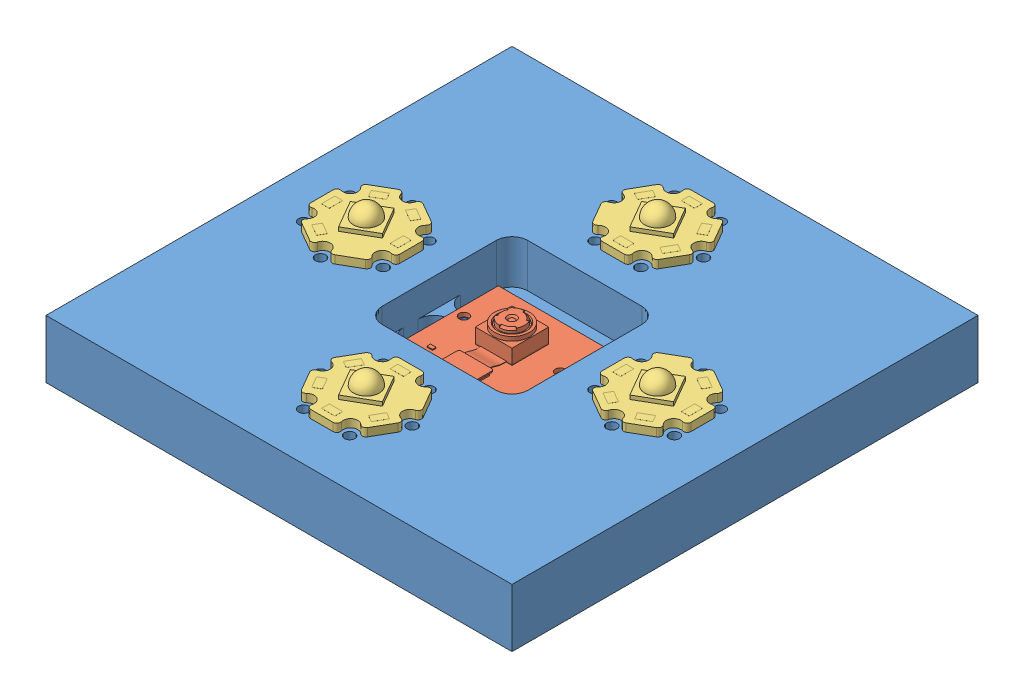
SolidWorks assembly Flashlight, configuration Default. Lengths in mm.
Overall size (101.6 18.1 101.6).
6 component instances, 3 part files, 5 mates.
Components (placement in the parent):
- LED Plate-1: LED Plate [Default] at (26.4563 39.58 55.3504) size (101.6 12.7 101.6)
- RasPi_Camera-1: RasPi_Camera [Default] at (26.4247 47.3817 55.2918) size (25 8.25 24)
- LZ4-40G108-0000-1: LZ4-40G108-0000 [Default] at (26.4563 52.28 23.6004) x (0.500598 0 0.86568) z (-0.86568 0 0.500598) size (19.46 5.4 19.4)
- LZ4-40G108-0000-2: LZ4-40G108-0000 [Default] at (-5.2937 52.28 55.3504) x (0.86568 0 -0.500598) z (0.500598 0 0.86568) size (19.46 5.4 19.4)
- LZ4-40G108-0000-3: LZ4-40G108-0000 [Default] at (26.4563 52.28 87.1004) x (-0.500598 0 -0.86568) z (0.86568 0 -0.500598) size (19.46 5.4 19.4)
- LZ4-40G108-0000-4: LZ4-40G108-0000 [Default] at (58.2063 52.28 55.3504) x (-0.86568 0 0.500598) z (-0.500598 0 -0.86568) size (19.46 5.4 19.4)
Mates (geometry in assembly coordinates):
- Coincident1: coincident anti-aligned: plane of LED Plate-1 through (26.4563 52.28 55.3504) normal (0 1 0); plane of LZ4-40G108-0000-1 through (26.4563 52.28 23.6004) normal (0 -1 0)
- Concentric1: concentric anti-aligned: circle of LZ4-40G108-0000-1; line of LED Plate-1 through (26.4563 52.28 23.6004) axis (0 1 0)
- Concentric3: concentric aligned: line of LED Plate-1 through (26.4563 39.58 55.3504) axis (0 1 0); circle of RasPi_Camera-1
- Parallel3: parallel aligned: plane of LED Plate-1 through (77.2563 52.28 4.5504) normal (1 0 0); plane of RasPi_Camera-1 through (38.9247 45.93 69.7918) normal (1 0 0)
- Coincident4: coincident anti-aligned: plane of LED Plate-1 through (15.9247 45.93 55.2918) normal (0 1 0); plane of RasPi_Camera-1 through (26.4247 45.93 55.2918) normal (0 -1 0)
